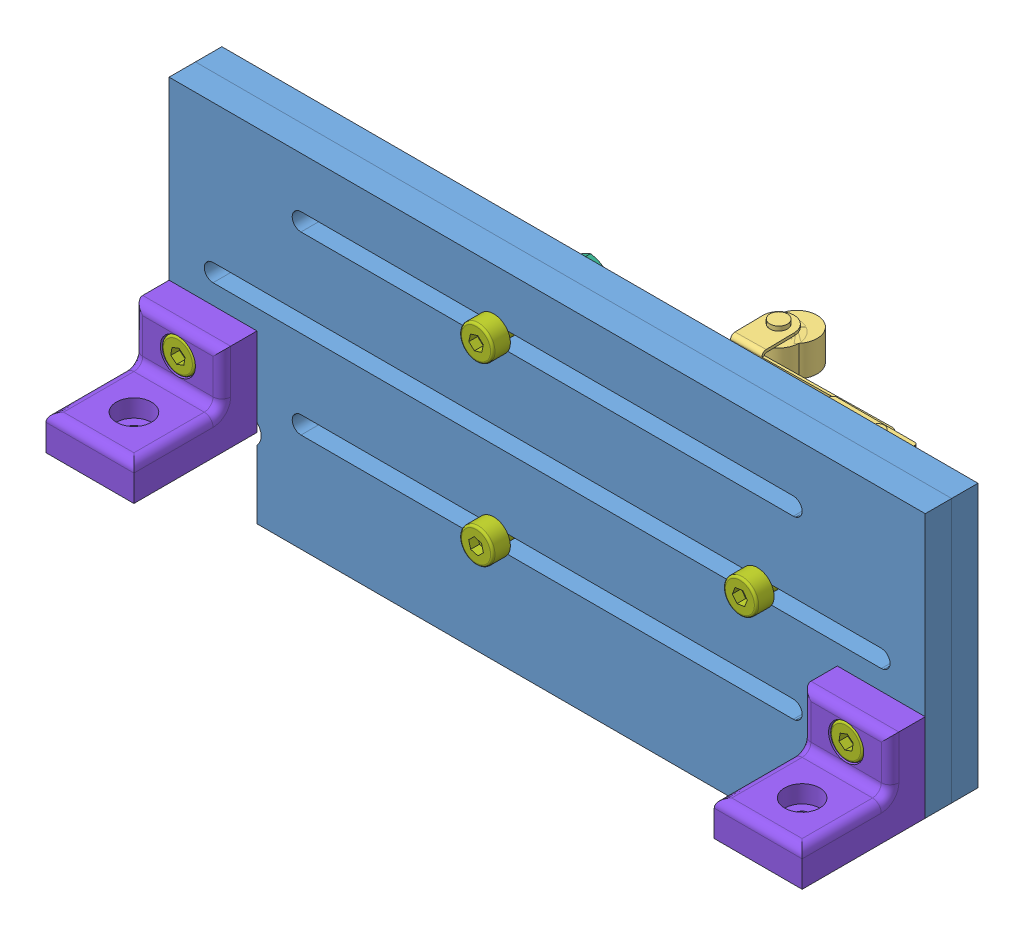
SolidWorks assembly cfc_ferme, configuration Défaut. Lengths in mm.
Overall size (86 39 42.4).
21 component instances, 8 part files, 46 mates.
Components (placement in the parent):
- cfc-platine-1: cfc-platine [Défaut] at (140.8628 -70 0) x (0 0 1) z (0 -1 0) size (3 86 39)
- Grove microswitch v1.0-1: Grove microswitch v1.0 [Défaut] at (-37.098 22.25 -3.344) x (1 0 0) z (0 1 0) size (41.8 22.4 23.6)
  - PCB grove 20x40-1: PCB grove 20x40 [Défaut] at (-1.988 -1.344 0) size (41.8 1.6 23.6)
  - microswitch 10T85-1: microswitch 10T85 [Défaut] at (9.562 0.256 0) size (22.48 22.4 6.4)
  - Connecteur Grove (coudé CMS)-1: Connecteur Grove (coudé CMS) [Défaut] at (-21.488 0.256 0) x (0 0 -1) z (0 1 0) size (12 10 5)
- entretoise-grove-1: entretoise-grove [Défaut] at (-19.086 22.25 -2) x (1 0.000242 0) z (0 0 1) size (4 4 2)
- entretoise-grove-2: entretoise-grove [Défaut] at (-49.086 12.25 -2) size (4 4 2)
- entretoise-grove-3: entretoise-grove [Défaut] at (-49.086 32.25 -2) size (4 4 2)
- ecrou-h-1: ecrou-h [6007 HU M2] at (-19.086 22.25 -3.6) x (0.5 0.866025 0) z (0.866025 -0.5 0) size (4 1.6 4.62)
- ecrou-h-2: ecrou-h [6007 HU M2] at (-49.086 12.25 -3.6) x (1 0 0) z (0 -1 0) size (4 1.6 4.62)
- ecrou-h-3: ecrou-h [6007 HU M2] at (-49.086 32.25 -3.6) x (-0.5 0.866025 0) z (0.866025 0.5 0) size (4 1.6 4.62)
- vis-chc-1: vis-chc [Vis CHC M2x12] at (-49.086 12.25 6) x (0.689734 0.724063 0) z (0.724063 -0.689734 0) size (3.8 14 3.8)
- vis-chc-2: vis-chc [Vis CHC M2x12] at (-49.086 32.25 6) x (-0.193562 -0.981088 0) z (-0.981088 0.193562 0) size (3.8 14 3.8)
- vis-chc-3: vis-chc [Vis CHC M2x12] at (-19.086 22.25 6) x (-0.643508 0.765439 0) z (0.765439 0.643508 0) size (3.8 14 3.8)
- ecrou-h-5: ecrou-h [6007 HU M2] at (-81 16 -1.6) x (1 0 0) z (0 1 0) size (4 1.6 4.62)
- ecrou-h-6: ecrou-h [6007 HU M2] at (-5 16 -1.6) x (1 0 0) z (0 1 0) size (4 1.6 4.62)
- vis-chc-6: vis-chc [Vis CHC M2x10] at (-5 16 8) x (-0.923728 -0.383049 0) z (-0.383049 0.923728 0) size (3.8 12 3.8)
- vis-chc-7: vis-chc [Vis CHC M2x10] at (-81 16 8) x (-0.923728 -0.383049 0) z (-0.383049 0.923728 0) size (3.8 12 3.8)
- cfc-platine-2: cfc-platine [Défaut] at (140.8628 -70 3) x (0 0 1) z (0 -1 0) size (3 86 39)
- equerre-basse-1: equerre-basse [Défaut] at (-81 9 6) size (10 10 14)
- equerre-basse-2: equerre-basse [Défaut] at (-5 9 6) size (10 10 14)
Mates (geometry in assembly coordinates):
- Coïncidente1: coincident anti-aligned: plane of cfc-platine-1 through (-8.8686 8.8686 0) normal (0 0 -1)
- Coïncidente2: coincident anti-aligned: plane of cfc-platine-1 through (-10 0 3) normal (0 -1 0)
- Coaxiale1: concentric anti-aligned: cylinder of Grove microswitch v1.0-1/PCB grove 20x40-1 through (-49.086 32.25 -3.6) axis (0 0 1) radius 1.1; cylinder of entretoise-grove-3 through (-49.086 32.25 0) axis (0 0 -1) radius 1.2
- Coïncidente4: coincident anti-aligned: plane of Grove microswitch v1.0-1/PCB grove 20x40-1 through (-39.086 22.25 -2) normal (0 0 1); plane of entretoise-grove-3 through (-49.086 32.25 -2) normal (0 0 -1)
- Coaxiale2: concentric anti-aligned: cylinder of Grove microswitch v1.0-1/PCB grove 20x40-1 through (-19.086 22.25 -3.6) axis (0 0 1) radius 1.1; cylinder of entretoise-grove-1 through (-19.086 22.25 0) axis (0 0 -1) radius 1.2
- Coïncidente5: coincident anti-aligned: plane of Grove microswitch v1.0-1/PCB grove 20x40-1 through (-39.086 22.25 -2) normal (0 0 1); plane of entretoise-grove-1 through (-19.086 22.25 -2) normal (0 0 -1)
- Coaxiale3: concentric anti-aligned: cylinder of Grove microswitch v1.0-1/PCB grove 20x40-1 through (-49.086 12.25 -3.6) axis (0 0 1) radius 1.1; cylinder of entretoise-grove-2 through (-49.086 12.25 0) axis (0 0 -1) radius 1.2
- Coïncidente6: coincident anti-aligned: plane of Grove microswitch v1.0-1/PCB grove 20x40-1 through (-39.086 22.25 -2) normal (0 0 1); plane of entretoise-grove-2 through (-49.086 12.25 -2) normal (0 0 -1)
- Coïncidente7: coincident anti-aligned: plane of cfc-platine-1 through (-8.8686 8.8686 0) normal (0 0 -1); plane of entretoise-grove-1 through (-19.086 22.25 0) normal (0 0 1)
- Parallèle4: parallel anti-aligned: plane of cfc-platine-1 through (-86 39 3) normal (-1 0 0); plane of Grove microswitch v1.0-1/PCB grove 20x40-1 through (-19.086 22.25 -3.6) normal (1 0 0)
- Parallèle3: parallel anti-aligned: plane of cfc-platine-1 through (-10 0 3) normal (0 -1 0); plane of Grove microswitch v1.0-1/PCB grove 20x40-1 through (-39.086 32.25 -3.6) normal (0 1 0)
- Coaxiale7: concentric aligned: cylinder of ecrou-h-2 through (-49.086 12.25 -5.2) axis (0 0 1) radius 0.7835; cylinder of vis-chc-1 through (-49.086 12.25 -6) axis (0 0 1) radius 1
- Coaxiale8: concentric aligned: cylinder of ecrou-h-3 through (-49.086 32.25 -5.2) axis (0 0 1) radius 0.7835; cylinder of vis-chc-2 through (-49.086 32.25 -6) axis (0 0 1) radius 1
- Coaxiale9: concentric aligned: cylinder of ecrou-h-1 through (-19.086 22.25 -5.2) axis (0 0 1) radius 0.7835; cylinder of vis-chc-3 through (-19.086 22.25 -6) axis (0 0 1) radius 1
- Tangent1: tangent anti-aligned: plane of cfc-platine-1 through (-5 21.25 3) normal (0 1 0); cylinder of vis-chc-3 through (-19.086 22.25 -6) axis (0 0 1) radius 1
- Coïncidente8: coincident anti-aligned: plane of Grove microswitch v1.0-1/PCB grove 20x40-1 through (-39.086 22.25 -3.6) normal (0 0 -1); plane of ecrou-h-1 through (-19.086 24.5594 -3.6) normal (0 0 1)
- Parallèle10: parallel anti-aligned: plane of Grove microswitch v1.0-1/microswitch 10T85-1 through (-21.086 25.25 -13.9) normal (1 0 0); plane of ecrou-h-1 through (-21.086 23.4047 -5.2) normal (-1 0 0)
- Coïncidente11: coincident anti-aligned: plane of Grove microswitch v1.0-1/PCB grove 20x40-1 through (-39.086 22.25 -3.6) normal (0 0 -1); plane of ecrou-h-2 through (-47.086 13.4047 -3.6) normal (0 0 1)
- Parallèle11: parallel anti-aligned: plane of cfc-platine-1 through (-86 39 3) normal (-1 0 0); plane of ecrou-h-2 through (-47.086 11.0953 -5.2) normal (1 0 0)
- Coïncidente13: coincident anti-aligned: plane of Grove microswitch v1.0-1/PCB grove 20x40-1 through (-39.086 22.25 -3.6) normal (0 0 -1); plane of ecrou-h-3 through (-51.086 33.4047 -3.6) normal (0 0 1)
- Parallèle12: parallel aligned: plane of cfc-platine-1 through (-86 39 3) normal (-1 0 0); plane of ecrou-h-3 through (-51.086 33.4047 -5.2) normal (-1 0 0)
- Coïncidente15: coincident anti-aligned: plane of cfc-platine-1 through (-8.8686 8.8686 3) normal (0 0 1); plane of cfc-platine-2 through (-8.8686 8.8686 3) normal (0 0 -1)
- Coïncidente16: coincident aligned: plane of cfc-platine-1 through (-10 0 3) normal (0 -1 0); plane of cfc-platine-2 through (-10 0 6) normal (0 -1 0)
- Coïncidente17: coincident aligned: plane of cfc-platine-1 through (-86 39 3) normal (-1 0 0); plane of cfc-platine-2 through (-86 39 6) normal (-1 0 0)
- Coïncidente19: coincident anti-aligned: plane of vis-chc-2 through (-49.086 32.25 6) normal (0 0 -1); plane of cfc-platine-2 through (-8.8686 8.8686 6) normal (0 0 1)
- Coaxiale10: concentric aligned: cylinder of Grove microswitch v1.0-1/PCB grove 20x40-1 through (-49.086 32.25 -3.6) axis (0 0 1) radius 1.1; cylinder of vis-chc-2 through (-49.086 32.25 -6) axis (0 0 1) radius 1
- Coaxiale11: concentric aligned: cylinder of Grove microswitch v1.0-1/PCB grove 20x40-1 through (-19.086 22.25 -3.6) axis (0 0 1) radius 1.1; cylinder of vis-chc-3 through (-19.086 22.25 -6) axis (0 0 1) radius 1
- Coïncidente21: coincident anti-aligned: plane of vis-chc-3 through (-19.086 22.25 6) normal (0 0 -1); plane of cfc-platine-2 through (-8.8686 8.8686 6) normal (0 0 1)
- Coïncidente22: coincident anti-aligned: plane of vis-chc-1 through (-49.086 12.25 6) normal (0 0 -1); plane of cfc-platine-2 through (-8.8686 8.8686 6) normal (0 0 1)
- Coaxiale12: concentric aligned: cylinder of Grove microswitch v1.0-1/PCB grove 20x40-1 through (-49.086 12.25 -3.6) axis (0 0 1) radius 1.1; cylinder of vis-chc-1 through (-49.086 12.25 -6) axis (0 0 1) radius 1
- Coïncidente23: coincident aligned: plane of cfc-platine-2 through (-78.726 9 6) normal (0 -1 0); plane of equerre-1 through (-86 9 10) normal (0 -1 0)
- Coïncidente24: coincident anti-aligned: plane of cfc-platine-2 through (-8.8686 8.8686 6) normal (0 0 1); plane of equerre-1 through (-81 9 6) normal (0 0 -1)
- Coaxiale13: concentric anti-aligned: cylinder of cfc-platine-2 through (-81 16 6) axis (0 0 -1) radius 1; cylinder of equerre-1 through (-81 16 6) axis (0 0 1) radius 1.1
- Coïncidente25: coincident anti-aligned: plane of cfc-platine-2 through (-8.8686 8.8686 6) normal (0 0 1); plane of equerre-2 through (-5 9 6) normal (0 0 -1)
- Coïncidente26: coincident aligned: plane of cfc-platine-2 through (0 9 6) normal (0 -1 0); plane of equerre-2 through (-10 9 10) normal (0 -1 0)
- Coaxiale14: concentric anti-aligned: cylinder of cfc-platine-2 through (-5 16 6) axis (0 0 -1) radius 1; cylinder of equerre-2 through (-5 16 6) axis (0 0 1) radius 1.1
- Coaxiale16: concentric aligned: cylinder of vis-chc-7 through (-81 16 -2) axis (0 0 1) radius 1; cylinder of equerre-1 through (-81 16 6) axis (0 0 1) radius 1.1
- Coaxiale17: concentric aligned: cylinder of vis-chc-6 through (-5 16 -2) axis (0 0 1) radius 1; cylinder of equerre-2 through (-5 16 6) axis (0 0 1) radius 1.1
- Coïncidente28: coincident anti-aligned: plane of vis-chc-6 through (-5 16 8) normal (0 0 -1); plane of equerre-2 through (-5 16 8) normal (0 0 1)
- Coïncidente29: coincident anti-aligned: plane of vis-chc-7 through (-81 16 8) normal (0 0 -1); plane of equerre-1 through (-81 16 8) normal (0 0 1)
- Coaxiale20: concentric anti-aligned: cylinder of ecrou-h-5 through (-81 16 0) axis (0 0 -1) radius 0.7835; cylinder of vis-chc-7 through (-81 16 -2) axis (0 0 1) radius 1
- Coïncidente33: coincident anti-aligned: plane of cfc-platine-1 through (-8.8686 8.8686 0) normal (0 0 -1); plane of ecrou-h-5 through (-79 14.8453 0) normal (0 0 1)
- Parallèle14: parallel aligned: plane of cfc-platine-1 through (-86 39 3) normal (-1 0 0); plane of ecrou-h-5 through (-83 14.8453 0) normal (-1 0 0)
- Coaxiale22: concentric anti-aligned: cylinder of ecrou-h-6 through (-5 16 0) axis (0 0 -1) radius 0.7835; cylinder of vis-chc-6 through (-5 16 -2) axis (0 0 1) radius 1
- Coïncidente35: coincident anti-aligned: plane of cfc-platine-1 through (-8.8686 8.8686 0) normal (0 0 -1); plane of ecrou-h-6 through (-3 14.8453 0) normal (0 0 1)
- Parallèle15: parallel aligned: plane of cfc-platine-1 through (0 9 3) normal (1 0 0); plane of ecrou-h-6 through (-3 17.1547 0) normal (1 0 0)
